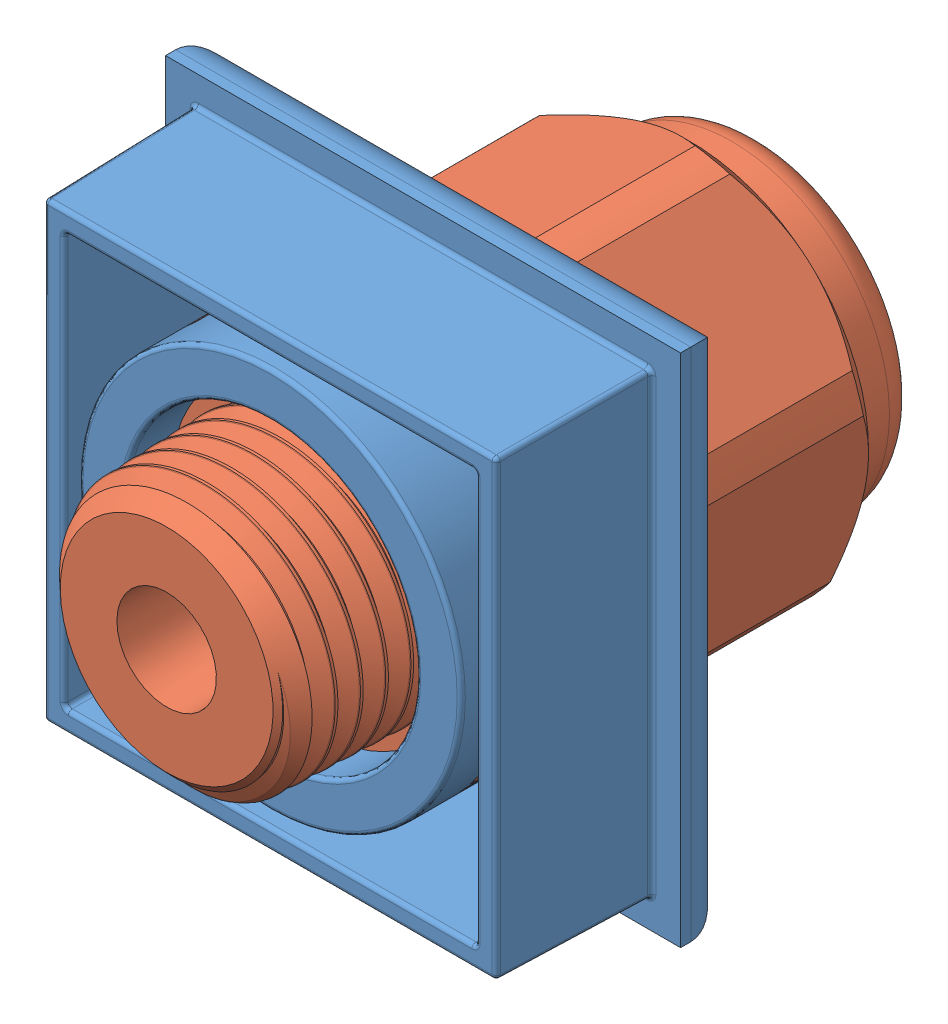
SolidWorks assembly gland_assembly, configuration Default. Lengths in mm.
Overall size (32.87 32.69 37.27).
3 component instances, 3 part files, 6 mates.
Components (placement in the parent):
- end_cap-1: end_cap [Default] at (-26.18 5.5496 6.8695) size (32.08 32.08 12.7)
- cord_grip_lrg-1: cord_grip_lrg [69915K52] at (-26.18 5.5496 12.2035) x (0 0 1) z (-0.779849 0.625967 0) (suppressed, hidden)
- cord_grip_sml-1: cord_grip_sml [69915K51] at (-26.18 5.5496 15.7253) x (0 0 1) z (-0.664747 -0.747069 0) size (37.27 24.34 22.1)
Mates (geometry in assembly coordinates):
- Coincident1: coincident: plane of end_cap-1 through (-26.18 5.5496 3.6945) normal (0 0 -1); plane of ? through (-26.18 5.5496 3.6945) normal (0 0 1)
- Concentric1: concentric: circle of end_cap-1; circle of ?
- Concentric2: concentric: circle of assembly; circle of assembly; circle of end_cap-1; circle of cord_grip_lrg-1
- Coincident2: coincident: plane of assembly; plane of assembly; plane of end_cap-1 through (-26.18 5.5496 6.8695) normal (0 0 1); plane of cord_grip_lrg-1 through (-26.18 5.5496 6.8695) normal (0 0 -1)
- Concentric3: concentric: circle of assembly; circle of assembly; circle of end_cap-1; circle of cord_grip_sml-1
- Coincident3: coincident: plane of end_cap-1 through (-26.18 5.5496 6.8695) normal (0 0 1); plane of ? through (-30.2295 15.315 6.8695) normal (0 0 -1)
